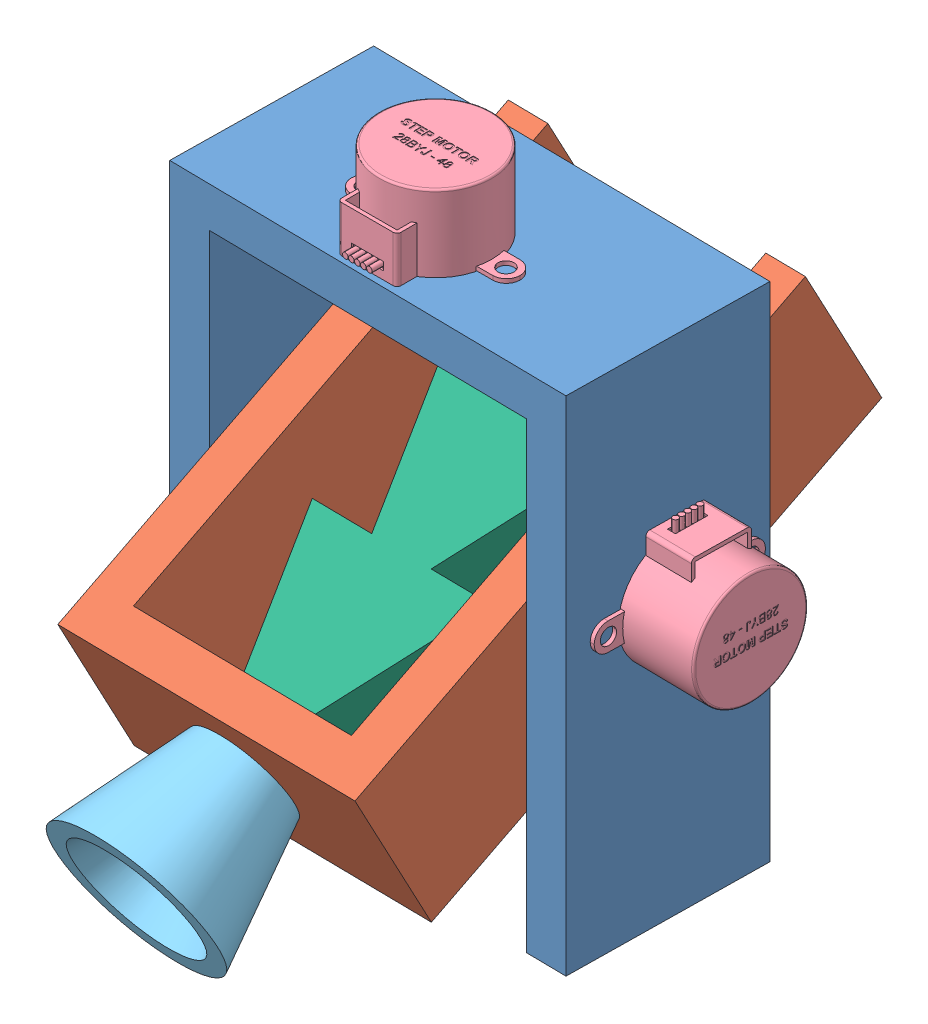
SolidWorks assembly Sprayer-Assembly, configuration Default. Lengths in mm.
Overall size (121.55 147.8 157.94).
7 component instances, 6 part files, 19 mates.
Components (placement in the parent):
- Sprayer-OuterPiece-1: Sprayer-OuterPiece [Default] at (7.38 -2 -25.48) x (0 1 0) z (-0.999896 0 -0.014453) size (125 50 100)
- Sprayer-InnerPiece-1: Sprayer-InnerPiece [Default] at (6.5819 -93.772 29.7356) x (0.01277 0.468352 -0.88345) z (0.999896 0 0.014453) size (125 40 98.1)
- Sprayer-Outer-Motor-Connector-1: Sprayer-Outer-Motor-Connector [Default] at (7.38 -13 -25.48) x (0.157394 0 -0.987536) z (0.987536 0 0.157394) size (10 14 11.55)
- 28BYJ-48-1: 28BYJ-48 [Varsayılan] at (78.2726 -56 -24.4553) x (0.014453 0 -0.999896) z (0 1 0) size (42 28.9 33.48)
- 28BYJ-48-2: 28BYJ-48 [Varsayılan] at (7.38 18.9 -16.98) x (-1 0 0) z (0 0 1) size (42 28.9 33.48)
- Sprayer-Nozzle-01-1: Sprayer-Nozzle-01 [Default] at (6.5819 -93.772 29.7356) x (0.01277 0.468352 -0.88345) z (0.985244 -0.156704 -0.068834) size (30 41.08 41.08)
- Sprayer-Junction-1: Sprayer-Junction [Default] at (-0.7389 -95.715 17.2805) x (0.01277 0.468352 -0.88345) z (0.006769 -0.883542 -0.468303) size (75 45 15)
Mates (geometry in assembly coordinates):
- Coincident1: coincident aligned: plane of 28BYJ-48-2 through (7.38 11.5 0) normal (0 0 1)
- Coincident2: coincident anti-aligned: plane of 28BYJ-48-2 through (0 11.5 -16.98) normal (-1 0 0)
- Coincident3: coincident anti-aligned: plane of 28BYJ-48-2 through (7.38 0 -16.98) normal (0 -1 0)
- Coincident4: coincident anti-aligned: plane of Sprayer-InnerPiece-1 through (6.5819 -93.772 29.7356) normal (-0.01277 -0.468352 0.88345); plane of Sprayer-Nozzle-01-1 through (6.5819 -93.772 29.7356) normal (0.01277 0.468352 -0.88345)
- Concentric1: concentric anti-aligned: cylinder of Sprayer-OuterPiece-1 through (47.3758 -64.5 -24.9019) axis (0.999896 0 0.014453) radius 4; cylinder of Sprayer-InnerPiece-1 through (56.4249 -64.5 -24.7711) axis (-0.999896 0 -0.014453) radius 3
- Concentric2: concentric anti-aligned: cylinder of Sprayer-OuterPiece-1 through (-32.6158 -64.5 -26.0581) axis (-0.999896 0 -0.014453) radius 4; cylinder of Sprayer-InnerPiece-1 through (-41.6649 -64.5 -26.1889) axis (0.999896 0 0.014453) radius 2.5
- Concentric3: concentric anti-aligned: cylinder of Sprayer-InnerPiece-1 through (56.4249 -64.5 -24.7711) axis (-0.999896 0 -0.014453) radius 3; cylinder of 28BYJ-48-1 through (49.3756 -64.5 -24.873) axis (0.999896 0 0.014453) radius 2.5
- Concentric4: concentric aligned: cylinder of Sprayer-OuterPiece-1 through (47.3758 -64.5 -24.9019) axis (0.999896 0 0.014453) radius 4; cylinder of 28BYJ-48-1 through (49.3756 -64.5 -24.873) axis (0.999896 0 0.014453) radius 2.5
- Concentric5: concentric aligned: cylinder of Sprayer-OuterPiece-1 through (7.38 -12 -25.48) axis (0 1 0) radius 4; cylinder of 28BYJ-48-2 through (7.38 -10 -25.48) axis (0 1 0) radius 2.5
- Concentric6: concentric anti-aligned: cylinder of Sprayer-Outer-Motor-Connector-1 through (7.38 -3 -25.48) axis (0 -1 0) radius 2.5; cylinder of 28BYJ-48-2 through (7.38 -10 -25.48) axis (0 1 0) radius 2.5
- Concentric7: concentric aligned: cylinder of Sprayer-InnerPiece-1 through (6.7096 -89.0885 20.9011) axis (-0.01277 -0.468352 0.88345) radius 2.5; circle of Sprayer-Nozzle-01-1
- Distance1: distance = 1 mm anti-aligned: plane of Sprayer-Outer-Motor-Connector-1 through (7.38 -3 -25.48) normal (0 1 0); plane of 28BYJ-48-2 through (7.38 -2 -25.48) normal (0 -1 0)
- Distance2: distance = 2 mm anti-aligned: plane of 28BYJ-48-1 through (59.3746 -56 -24.7284) normal (-0.999896 0 -0.014453); plane of Sprayer-OuterPiece-1 through (57.7361 -12 -49.7547) normal (0.999896 0 0.014453)
- Distance3: distance = 2 mm anti-aligned: plane of Sprayer-OuterPiece-1 through (7.38 -2 -25.48) normal (0 1 0); plane of 28BYJ-48-2 through (7.38 0 -16.98) normal (0 -1 0)
- Parallel1: parallel aligned: plane of Sprayer-OuterPiece-1 through (7.38 -2 -25.48) normal (0 1 0); plane of 28BYJ-48-1 through (70.8734 -39.02 -24.5622) normal (0 1 0)
- Width1: width anti-aligned: plane of Sprayer-OuterPiece-1 through (-32.6158 -2 -26.0581) normal (0.999896 0 0.014453); plane of Sprayer-InnerPiece-1 through (47.3758 -2 -24.9019) normal (-0.999896 0 -0.014453); plane of Sprayer-OuterPiece-1 through (-30.9219 -71.4176 29.7252) normal (-0.999896 0 -0.014453); plane of Sprayer-InnerPiece-1 through (44.0703 -71.4176 30.8092) normal (0.999896 0 0.014453)
- Concentric8: concentric anti-aligned: circle of Sprayer-InnerPiece-1; circle of Sprayer-Junction-1
- Coincident5: coincident anti-aligned: plane of Sprayer-InnerPiece-1 through (6.7096 -89.0885 20.9011) normal (0.01277 0.468352 -0.88345); plane of Sprayer-Junction-1 through (14.2596 -95.715 17.4972) normal (-0.01277 -0.468352 0.88345)
- Parallel2: parallel aligned: plane of Sprayer-InnerPiece-1 through (44.0703 -71.4176 30.8092) normal (-0.006769 0.883542 0.468303); plane of Sprayer-Junction-1 through (14.158 -82.4619 24.5218) normal (-0.006769 0.883542 0.468303)
